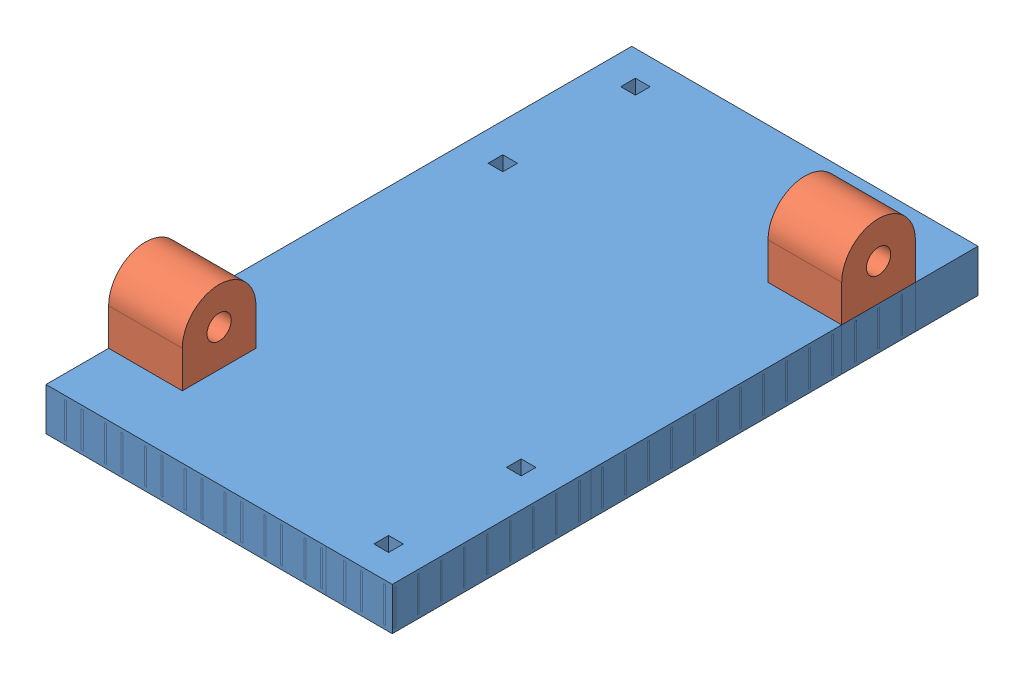
SolidWorks assembly openroach_5.1_base_assembly_SLDWRKS_2010, configuration Default. Lengths in mm.
Overall size (47 15.8 79.5).
3 component instances, 2 part files, 6 mates.
Components (placement in the parent):
- openroach_5.1_base_hexfill_SLDWRKS_2010-1: openroach_5.1_base_hexfill_SLDWRKS_2010 [Default] at origin size (47 5.8 79.5)
- openroach_5.1_base_shaft_mount_SLDWRKS_2010-1: openroach_5.1_base_shaft_mount_SLDWRKS_2010 [Default] at (10.4822 7.9 -10.4014) x (0 0 1) z (-1 0 0) size (10 10 10)
- openroach_5.1_base_shaft_mount_SLDWRKS_2010-2: openroach_5.1_base_shaft_mount_SLDWRKS_2010 [Default] at (37.4823 7.9 -62.9034) x (0 0 -1) z (1 0 0) size (10 10 10)
Mates (geometry in assembly coordinates):
- Coincident3: coincident anti-aligned: plane of openroach_5.1_base_hexfill_SLDWRKS_2010-1 through (23.9823 2.9 -108.6298) normal (0 1 0); plane of openroach_5.1_base_shaft_mount_SLDWRKS_2010-1 through (0.4822 2.9 -5.4014) normal (0 -1 0)
- Distance3: distance = 8.5 mm aligned: plane of openroach_5.1_base_shaft_mount_SLDWRKS_2010-1 through (0.4822 7.9 -5.4014) normal (0 0 1); plane of openroach_5.1_base_hexfill_SLDWRKS_2010-1 through (38.4821 2.9 3.0986) normal (0 0 1)
- Coincident6: coincident aligned: plane of openroach_5.1_base_hexfill_SLDWRKS_2010-1 through (0.4822 2.9 -15.4017) normal (-1 0 0); plane of openroach_5.1_base_shaft_mount_SLDWRKS_2010-1 through (0.4822 7.9 -10.4014) normal (-1 0 0)
- Coincident7: coincident anti-aligned: plane of openroach_5.1_base_hexfill_SLDWRKS_2010-1 through (23.9823 2.9 -108.6298) normal (0 1 0); plane of openroach_5.1_base_shaft_mount_SLDWRKS_2010-2 through (47.4823 2.9 -67.9034) normal (0 -1 0)
- Distance4: distance = 8.5 mm aligned: plane of openroach_5.1_base_shaft_mount_SLDWRKS_2010-2 through (47.4823 7.9 -67.9034) normal (0 0 -1); plane of openroach_5.1_base_hexfill_SLDWRKS_2010-1 through (-54.6633 2.4 -76.4034) normal (0 0 -1)
- Coincident8: coincident aligned: plane of openroach_5.1_base_hexfill_SLDWRKS_2010-1 through (47.4823 2.9 -57.9031) normal (1 0 0); plane of openroach_5.1_base_shaft_mount_SLDWRKS_2010-2 through (47.4823 7.9 -62.9034) normal (1 0 0)
